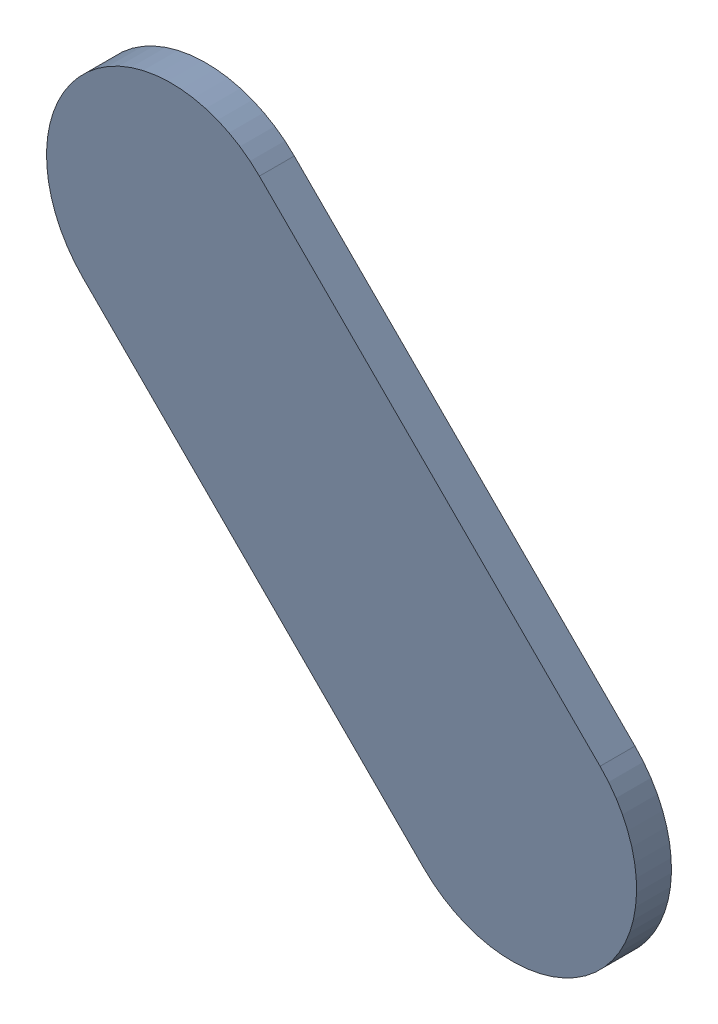
SolidWorks assembly Track (27.19mm,44.778mm)(27.537mm,44.431mm) on Top Layer, configuration Predeterminado. Lengths in mm.
Overall size (0.6 0.6 0.04).
2 component instances, 1 part files, 0 mates.
Components (placement in the parent):
- Track (27.19mm,44.778mm)(27.537mm,44.431mm) on Top Layer-1-1: Track (27.19mm,44.778mm)(27.537mm,44.431mm) on Top Layer-1 [Predeterminado] at (-68.317 -44.187 -0.0457) size (0.6 0.6 0.04)
  - Track (27.19mm,44.778mm)(27.537mm,44.431mm) on Top Layer-Part-1-1: Track (27.19mm,44.778mm)(27.537mm,44.431mm) on Top Layer-Part-1 [Predeterminado] at origin size (0.6 0.6 0.04)
